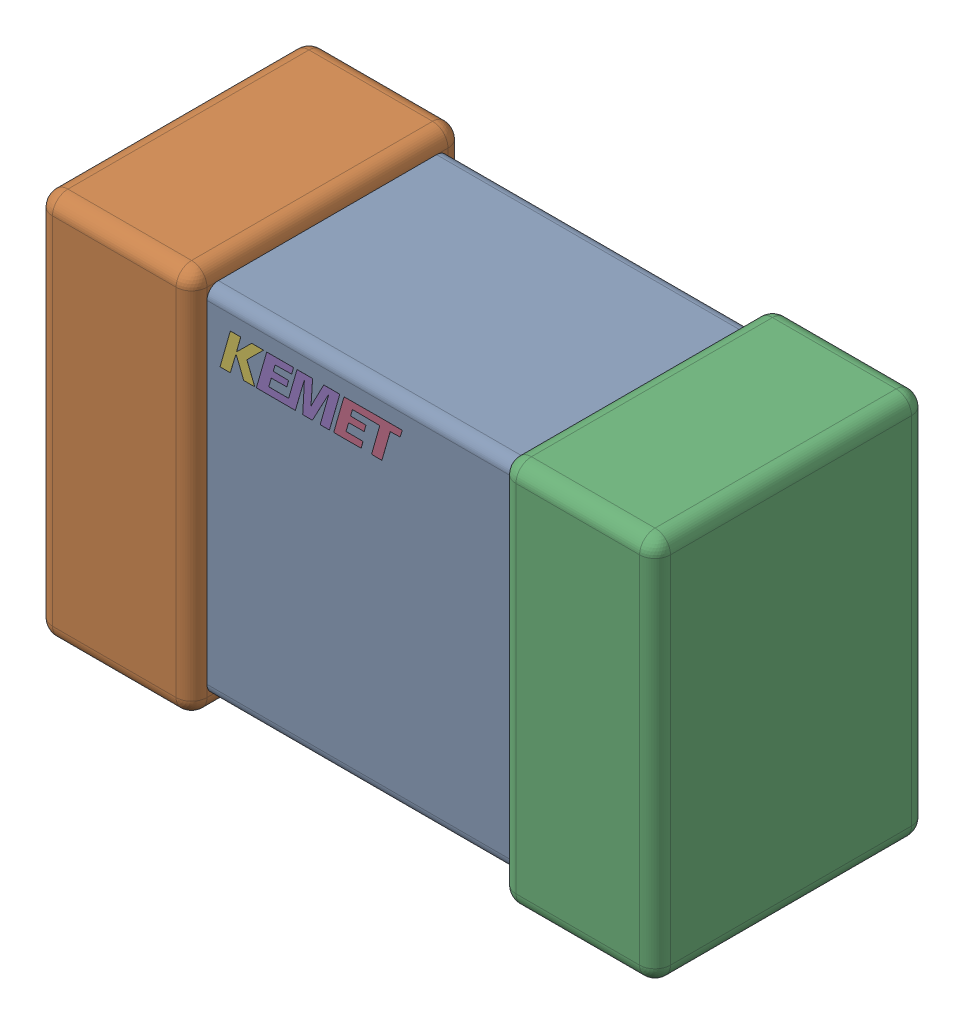
SolidWorks assembly C14.step, configuration Default. Lengths in mm.
Overall size (2 1.25 0.88).
3 component instances, 3 part files, 0 mates.
Components (placement in the parent):
- Cap_KEMET_C0805C472J3HAC_eec.step-1: Cap_KEMET_C0805C472J3HAC_eec.step [Default] at (57.277 2.667 0) size (1 1.15 0.78)
- Cap_KEMET_C0805C472J3HAC_eec-7.step-1: Cap_KEMET_C0805C472J3HAC_eec-7.step [Default] at (57.277 2.667 0) size (2 1.25 0.88)
- Cap_KEMET_C0805C472J3HAC_eec-8.step-1: Cap_KEMET_C0805C472J3HAC_eec-8.step [Default] at (57.277 2.667 0) size (0.59 0.12 0)
